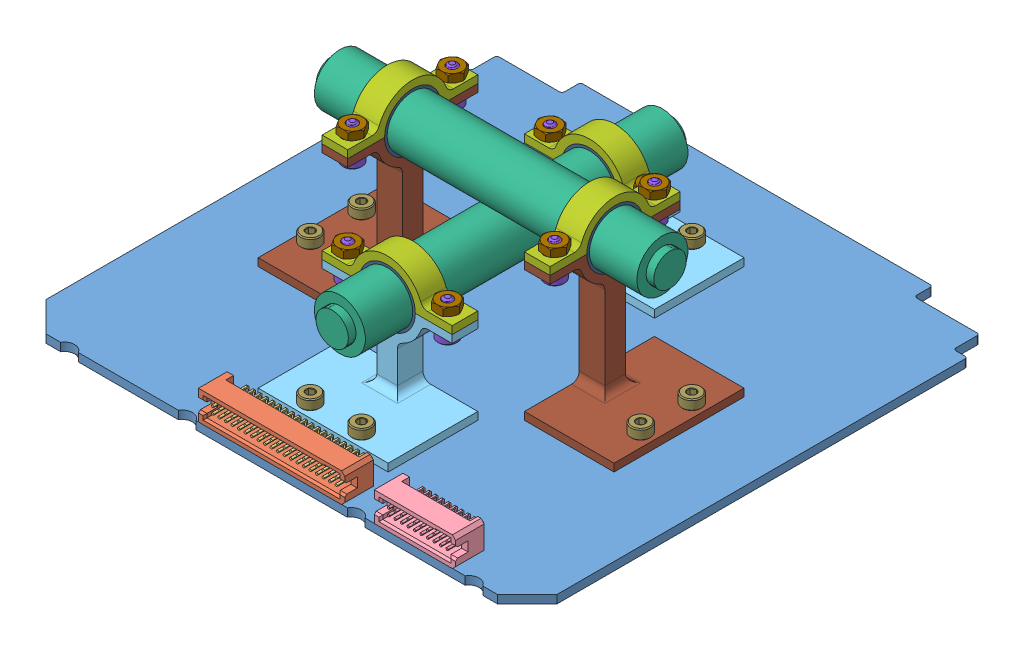
SolidWorks assembly ADACSCard, configuration Default. Lengths in mm.
Overall size (99.8 38.85 94.73).
53 component instances, 12 part files, 29 mates.
Components (placement in the parent):
- ADACSPCB-1: ADACSPCB [Default] at origin size (99.8 1.6 94.7)
- TFM_120_01_L_D_RA-1: TFM_120_01_L_D_RA [Default] at (0 3.6575 39.237) x (1 0 0) z (0 -1 0) size (28.58 7.49 7.62)
  - _TFM_120_01_L_D_RA_terminal_2-1: _TFM_120_01_L_D_RA_terminal_2 [Default] at origin size (28.58 5.59 5.72)
  - _TFM_120_01_L_D_RA_pins_4-1: _TFM_120_01_L_D_RA_pins_4 [Default] at origin size (25.4 6.95 5.84)
- TFM_110_01_L_D_RA_defeature-1: TFM_110_01_L_D_RA_defeature [Default] at (28 3.6575 39.237) x (1 0 0) z (0 -1 0) size (15.88 7.49 7.62)
- Linear_Short-1: Linear_Short [Default] at (21.8184 7.5306 9.4489) size (25.79 24 69.52)
  - Bracket_Base_Short-1: Bracket_Base_Short [Default] at (-21.8184 10.2694 10.3111) size (25.4 17 17.5)
  - Bracket_Base_Short-2: Bracket_Base_Short [Default] at (-21.8184 10.2694 -29.2089) x (-1 0 0) z (0 0 -1) size (25.4 17 17.5)
  - Linear_Magnetorquer-1: Linear_Magnetorquer [Default] at (-21.8184 10.2694 -9.4489) size (10 10 66)
  - Bracket_Top-1: Bracket_Top [Default] at (-21.8184 10.2694 -29.2089) x (-1 0 0) z (0 0 1) size (25.4 7 5)
  - Bracket_Top-2: Bracket_Top [Default] at (-21.8184 10.2694 10.3111) x (-1 0 0) z (0 0 1) size (25.4 7 5)
  - 92290A012_TYPE 316 SS SOCKET HEAD CAP SCREW-1: 92290A012_TYPE 316 SS SOCKET HEAD CAP SCREW [92290A012] at (-32.0184 13.7694 10.3111) x (0.961804 0 0.273737) z (0 1 0) size (3.8 3.8 7.44)
  - 92290A012_TYPE 316 SS SOCKET HEAD CAP SCREW-2: 92290A012_TYPE 316 SS SOCKET HEAD CAP SCREW [92290A012] at (-32.0184 13.7694 -29.2089) x (0.961804 0 0.273737) z (0 1 0) size (3.8 3.8 7.44)
  - 92290A012_TYPE 316 SS SOCKET HEAD CAP SCREW-3: 92290A012_TYPE 316 SS SOCKET HEAD CAP SCREW [92290A012] at (-12.5184 13.7694 10.3111) x (0.961804 0 0.273737) z (0 1 0) size (3.8 3.8 7.44)
  - 92290A012_TYPE 316 SS SOCKET HEAD CAP SCREW-4: 92290A012_TYPE 316 SS SOCKET HEAD CAP SCREW [92290A012] at (-12.5184 13.7694 -29.2089) x (0.961804 0 0.273737) z (0 1 0) size (3.8 3.8 7.44)
  - 91828A111_TYPE 18-8 STAINLESS STEEL HEX NUT-1: 91828A111_TYPE 18-8 STAINLESS STEEL HEX NUT [91828A111] at (-32.0184 12.5694 10.3111) x (0.866025 0 0.5) z (0 -1 0) size (4 4.62 1.83)
  - 91828A111_TYPE 18-8 STAINLESS STEEL HEX NUT-2: 91828A111_TYPE 18-8 STAINLESS STEEL HEX NUT [91828A111] at (-12.5184 12.5694 10.3111) x (0.866025 0 0.5) z (0 -1 0) size (4 4.62 1.83)
  - 91828A111_TYPE 18-8 STAINLESS STEEL HEX NUT-3: 91828A111_TYPE 18-8 STAINLESS STEEL HEX NUT [91828A111] at (-32.0184 12.5694 -29.2089) x (0.866025 0 0.5) z (0 -1 0) size (4 4.62 1.83)
  - 91828A111_TYPE 18-8 STAINLESS STEEL HEX NUT-4: 91828A111_TYPE 18-8 STAINLESS STEEL HEX NUT [91828A111] at (-12.5184 12.5694 -29.2089) x (0.866025 0 0.5) z (0 -1 0) size (4 4.62 1.83)
  - Rubber_grip-1: Rubber_grip [Default] at (-21.8184 10.2694 7.8111) size (11 11 5)
  - Rubber_grip-2: Rubber_grip [Default] at (-21.8184 10.2694 -31.7089) size (11 11 5)
- Linear_Tall-1: Linear_Tall [Default] at (2.179 16.0694 39.2977) x (0 0 1) z (-1 0 0) size (25.9 34 69.52)
  - Bracket_Base_Tall-1: Bracket_Base_Tall [Default] at (-39.2977 11.7306 21.939) size (25.4 27 17.5)
  - Bracket_Base_Tall-2: Bracket_Base_Tall [Default] at (-39.2977 11.7306 -17.581) x (-1 0 0) z (0 0 -1) size (25.4 27 17.5)
  - Linear_Magnetorquer-1: Linear_Magnetorquer [Default] at (-39.2977 11.7306 2.179) x (-1 0 0) z (0 0 1) size (10 10 66)
  - Bracket_Top-1: Bracket_Top [Default] at (-39.2977 11.7306 21.939) x (-1 0 0) z (0 0 1) size (25.4 7 5)
  - Bracket_Top-2: Bracket_Top [Default] at (-39.2977 11.7306 -17.581) x (-1 0 0) z (0 0 1) size (25.4 7 5)
  - 92290A012_TYPE 316 SS SOCKET HEAD CAP SCREW-1: 92290A012_TYPE 316 SS SOCKET HEAD CAP SCREW [92290A012] at (-49.4977 15.2306 21.939) x (1 0 0) z (0 1 0) size (3.8 3.8 7.44)
  - 92290A012_TYPE 316 SS SOCKET HEAD CAP SCREW-3: 92290A012_TYPE 316 SS SOCKET HEAD CAP SCREW [92290A012] at (-49.4977 15.2306 -17.581) x (1 0 0) z (0 1 0) size (3.8 3.8 7.44)
  - 92290A012_TYPE 316 SS SOCKET HEAD CAP SCREW-4: 92290A012_TYPE 316 SS SOCKET HEAD CAP SCREW [92290A012] at (-29.9977 15.2306 21.939) x (1 0 0) z (0 1 0) size (3.8 3.8 7.44)
  - 92290A012_TYPE 316 SS SOCKET HEAD CAP SCREW-5: 92290A012_TYPE 316 SS SOCKET HEAD CAP SCREW [92290A012] at (-29.9977 15.2306 -17.581) x (1 0 0) z (0 1 0) size (3.8 3.8 7.44)
  - 91828A111_TYPE 18-8 STAINLESS STEEL HEX NUT-1: 91828A111_TYPE 18-8 STAINLESS STEEL HEX NUT [91828A111] at (-49.4977 14.0306 21.939) x (-0.5 0 0.866025) z (0 -1 0) size (4 4.62 1.83)
  - 91828A111_TYPE 18-8 STAINLESS STEEL HEX NUT-2: 91828A111_TYPE 18-8 STAINLESS STEEL HEX NUT [91828A111] at (-29.9977 14.0306 21.939) x (-0.5 0 0.866025) z (0 -1 0) size (4 4.62 1.83)
  - 91828A111_TYPE 18-8 STAINLESS STEEL HEX NUT-3: 91828A111_TYPE 18-8 STAINLESS STEEL HEX NUT [91828A111] at (-49.4977 14.0306 -17.581) x (-0.5 0 0.866025) z (0 -1 0) size (4 4.62 1.83)
  - 91828A111_TYPE 18-8 STAINLESS STEEL HEX NUT-4: 91828A111_TYPE 18-8 STAINLESS STEEL HEX NUT [91828A111] at (-29.9977 14.0306 -17.581) x (-0.5 0 0.866025) z (0 -1 0) size (4 4.62 1.83)
  - Rubber_grip-1: Rubber_grip [Default] at (-39.2977 11.7306 19.439) size (11 11 5)
  - Rubber_grip-2: Rubber_grip [Default] at (-39.2977 11.7306 -20.081) size (11 11 5)
- 91828A111_TYPE 18-8 STAINLESS STEEL HEX NUT-1: 91828A111_TYPE 18-8 STAINLESS STEEL HEX NUT [91828A111] at (-32.26 -1.6 -5) x (-1 0 0) z (0 -1 0) size (4 4.62 1.83)
- 91828A111_TYPE 18-8 STAINLESS STEEL HEX NUT-2: 91828A111_TYPE 18-8 STAINLESS STEEL HEX NUT [91828A111] at (-5 -1.6 -32.26) x (0 0 -1) z (0 -1 0) size (4 4.62 1.83)
- 91828A111_TYPE 18-8 STAINLESS STEEL HEX NUT-3: 91828A111_TYPE 18-8 STAINLESS STEEL HEX NUT [91828A111] at (5 -1.6 -32.26) x (0 0 -1) z (0 -1 0) size (4 4.62 1.83)
- 91828A111_TYPE 18-8 STAINLESS STEEL HEX NUT-4: 91828A111_TYPE 18-8 STAINLESS STEEL HEX NUT [91828A111] at (-5 -1.6 32.26) x (0 0 -1) z (0 -1 0) size (4 4.62 1.83)
- 91828A111_TYPE 18-8 STAINLESS STEEL HEX NUT-5: 91828A111_TYPE 18-8 STAINLESS STEEL HEX NUT [91828A111] at (5 -1.6 32.26) x (0 0 -1) z (0 -1 0) size (4 4.62 1.83)
- 91828A111_TYPE 18-8 STAINLESS STEEL HEX NUT-6: 91828A111_TYPE 18-8 STAINLESS STEEL HEX NUT [91828A111] at (32.26 -1.6 -5) x (-1 0 0) z (0 -1 0) size (4 4.62 1.83)
- 91828A111_TYPE 18-8 STAINLESS STEEL HEX NUT-7: 91828A111_TYPE 18-8 STAINLESS STEEL HEX NUT [91828A111] at (-32.26 -1.6 5) x (-1 0 0) z (0 -1 0) size (4 4.62 1.83)
- 91828A111_TYPE 18-8 STAINLESS STEEL HEX NUT-8: 91828A111_TYPE 18-8 STAINLESS STEEL HEX NUT [91828A111] at (32.26 -1.6 5) x (-1 0 0) z (0 -1 0) size (4 4.62 1.83)
- 92290A013_TYPE 316 SS SOCKET HEAD CAP SCREW-1: 92290A013_TYPE 316 SS SOCKET HEAD CAP SCREW [92290A013] at (-32.26 -3.7 5) x (1 0 0) z (0 -1 0) size (3.8 3.8 8.44)
- 92290A013_TYPE 316 SS SOCKET HEAD CAP SCREW-2: 92290A013_TYPE 316 SS SOCKET HEAD CAP SCREW [92290A013] at (-5 -3.7 32.26) x (1 0 0) z (0 -1 0) size (3.8 3.8 8.44)
- 92290A013_TYPE 316 SS SOCKET HEAD CAP SCREW-3: 92290A013_TYPE 316 SS SOCKET HEAD CAP SCREW [92290A013] at (32.26 -3.7 5) x (1 0 0) z (0 -1 0) size (3.8 3.8 8.44)
- 92290A013_TYPE 316 SS SOCKET HEAD CAP SCREW-4: 92290A013_TYPE 316 SS SOCKET HEAD CAP SCREW [92290A013] at (-32.26 -3.7 -5) x (1 0 0) z (0 -1 0) size (3.8 3.8 8.44)
- 92290A013_TYPE 316 SS SOCKET HEAD CAP SCREW-5: 92290A013_TYPE 316 SS SOCKET HEAD CAP SCREW [92290A013] at (32.26 -3.7 -5) x (1 0 0) z (0 -1 0) size (3.8 3.8 8.44)
- 92290A013_TYPE 316 SS SOCKET HEAD CAP SCREW-6: 92290A013_TYPE 316 SS SOCKET HEAD CAP SCREW [92290A013] at (-5 -3.7 -32.26) x (1 0 0) z (0 -1 0) size (3.8 3.8 8.44)
- 92290A013_TYPE 316 SS SOCKET HEAD CAP SCREW-7: 92290A013_TYPE 316 SS SOCKET HEAD CAP SCREW [92290A013] at (5 -3.7 32.26) x (1 0 0) z (0 -1 0) size (3.8 3.8 8.44)
- 92290A013_TYPE 316 SS SOCKET HEAD CAP SCREW-8: 92290A013_TYPE 316 SS SOCKET HEAD CAP SCREW [92290A013] at (5 -3.7 -32.26) x (1 0 0) z (0 -1 0) size (3.8 3.8 8.44)
Mates (geometry in assembly coordinates):
- Coincident1: coincident anti-aligned: plane of ADACSPCB-1 through (0 0.8 0) normal (0 1 0); plane of TFM_120_01_L_D_RA-1/_TFM_120_01_L_D_RA_terminal_2-1 through (-14.2875 0.8 44.825) normal (0 -1 0)
- Coincident2: coincident: line of ADACSPCB-1 through (49.9 0.8 37.332) axis (-1 0 0); plane of TFM_120_01_L_D_RA-1/_TFM_120_01_L_D_RA_pins_4-1 through (0 3.6575 37.332) normal (0 0 -1)
- Coincident3: coincident: line of ADACSPCB-1 through (0 0.8 -5.2282) axis (0 0 1); plane of TFM_120_01_L_D_RA-1/_TFM_120_01_L_D_RA_terminal_2-1 through (0 3.6575 39.237) normal (1 0 0)
- Coincident4: coincident anti-aligned: plane of ADACSPCB-1 through (0 0.8 0) normal (0 1 0); plane of TFM_110_01_L_D_RA_defeature-1 through (20.0625 0.8 44.825) normal (0 -1 0)
- Coincident5: coincident: line of ADACSPCB-1 through (28 0.8 48.6679) axis (0 0 -1); plane of TFM_110_01_L_D_RA_defeature-1 through (28 3.6575 39.237) normal (1 0 0)
- Coincident6: coincident: line of ADACSPCB-1 through (49.9 0.8 37.332) axis (-1 0 0); plane of TFM_110_01_L_D_RA_defeature-1 through (28 3.6575 37.332) normal (0 0 -1)
- Coincident7: coincident aligned: plane of Linear_Short-1/Linear_Magnetorquer-1 through (0 17.8 0) normal (1 0 0)
- Coincident9: coincident anti-aligned: plane of Linear_Tall-1/Linear_Magnetorquer-1 through (0 27.8 0) normal (0 0 -1)
- Coincident11: coincident anti-aligned: plane of Linear_Tall-1/Linear_Magnetorquer-1 through (0 27.8 0) normal (-1 0 0)
- Coincident12: coincident aligned: plane of Linear_Short-1/Linear_Magnetorquer-1 through (0 17.8 0) normal (0 0 1)
- Concentric1: concentric aligned: circle of ADCScard-1; circle of 94150A115_316 STAINLESS STEEL HEX NUT-1
- Coincident15: coincident anti-aligned: plane of ADACSPCB-1 through (0 -0.8 0) normal (0 -1 0); plane of 94150A115_316 STAINLESS STEEL HEX NUT-1 through (-1.6798 -0.8 -28.0291) normal (0 1 0)
- Coincident17: coincident anti-aligned: plane of ADACSPCB-1 through (0 -0.8 0) normal (0 -1 0); plane of 94150A115_316 STAINLESS STEEL HEX NUT-2 through (25.5802 -0.8 -0.7691) normal (0 1 0)
- Concentric2: concentric aligned: circle of ADCScard-1; circle of 94150A115_316 STAINLESS STEEL HEX NUT-2
- Coincident23: coincident aligned: circle of ADACSPCB-1; circle of Linear_Tall-1/Bracket_Base_Tall-1
- Coincident24: coincident aligned: circle of ADACSPCB-1; circle of Linear_Tall-1/Bracket_Base_Tall-1
- Coincident25: coincident aligned: circle of ADACSPCB-1; circle of Linear_Short-1/Bracket_Base-1
- Concentric3: concentric anti-aligned: circle of ADACSPCB-1; circle of 91828A111_TYPE 18-8 STAINLESS STEEL HEX NUT-1
- Coincident26: coincident anti-aligned: plane of ADACSPCB-1 through (0 -0.8 0) normal (0 -1 0); plane of 91828A111_TYPE 18-8 STAINLESS STEEL HEX NUT-1 through (-30.26 -0.8 -6.1547) normal (0 1 0)
- Parallel1: parallel aligned: plane of ADACSPCB-1 through (-49.9 -0.8 0) normal (-1 0 0); plane of 91828A111_TYPE 18-8 STAINLESS STEEL HEX NUT-1 through (-34.26 -2.4 -3.8453) normal (-1 0 0)
- Coincident28: coincident anti-aligned: plane of ADACSPCB-1 through (0 -0.8 0) normal (0 -1 0); plane of 91828A111_TYPE 18-8 STAINLESS STEEL HEX NUT-2 through (-3.8453 -0.8 -30.26) normal (0 1 0)
- Concentric4: concentric aligned: circle of 91828A111_TYPE 18-8 STAINLESS STEEL HEX NUT-2; circle of ADACSPCB-1
- Parallel2: parallel aligned: plane of 91828A111_TYPE 18-8 STAINLESS STEEL HEX NUT-2 through (-6.1547 -2.4 -34.26) normal (0 0 -1); plane of ADACSPCB-1 through (0 -0.8 -49.9) normal (0 0 -1)
- Concentric5: concentric anti-aligned: circle of Linear_Tall-1/Bracket_Base_Tall-1; circle of 92290A013_TYPE 316 SS SOCKET HEAD CAP SCREW-1
- Coincident30: coincident anti-aligned: plane of Linear_Tall-1/Bracket_Base_Tall-1 through (-19.76 2.3 0) normal (0 1 0); plane of 92290A013_TYPE 316 SS SOCKET HEAD CAP SCREW-1 through (-32.26 2.3 5) normal (0 -1 0)
- Concentric6: concentric anti-aligned: cylinder of Linear_Short-1/Bracket_Base-1 through (-5 0.8 32.26) axis (0 1 0) radius 1.2; cylinder of 92290A013_TYPE 316 SS SOCKET HEAD CAP SCREW-2 through (-5 4.3 32.26) axis (0 -1 0) radius 1.9
- Coincident31: coincident anti-aligned: plane of Linear_Short-1/Bracket_Base-1 through (0 2.3 19.76) normal (0 1 0); plane of 92290A013_TYPE 316 SS SOCKET HEAD CAP SCREW-2 through (-5 2.3 32.26) normal (0 -1 0)
- Parallel3: parallel aligned: plane of 92290A013_TYPE 316 SS SOCKET HEAD CAP SCREW-1 through (-32.26 -3.7 5) normal (1 0 0)
- Parallel4: parallel aligned: plane of 92290A013_TYPE 316 SS SOCKET HEAD CAP SCREW-2 through (-5 -3.7 32.26) normal (1 0 0)
